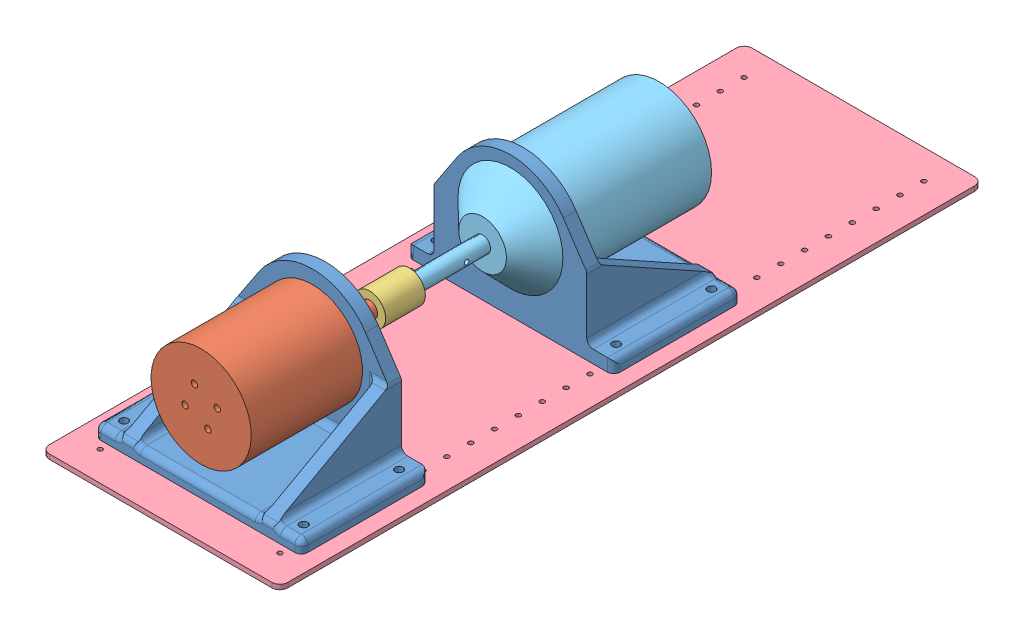
SolidWorks assembly test bed assembly, configuration Default. Lengths in mm.
Overall size (150 92.16 442).
10 component instances, 5 part files, 17 mates.
Components (placement in the parent):
- motor mount-1: motor mount [Default] at (42.5731 -25.4592 0) size (130 88 80)
- Eapmic C6374-1: Eapmic C6374 [Default] at (42.5731 -25.4592 8) x (-0.923728 -0.383049 0) z (0 0 -1) size (63 63 114)
- coupling-1: coupling [Default] at (42.5731 -25.4592 -40.5) size (20 20 25)
- fixture plate-1: fixture plate [Default] at (117.5731 -76.4592 103.5) x (0 0 -1) z (1 0 0) size (442 3 150)
- Flipsky 4125^test bed assembly-1: Flipsky 4125^test bed assembly [Default] at origin (suppressed, hidden, virtual)
- Flipsky 5062^test bed assembly-1: Flipsky 5062^test bed assembly [Default] at origin (suppressed, hidden, virtual)
- Flipsky 5085^test bed assembly-1: Flipsky 5085^test bed assembly [Default] at origin (suppressed, hidden, virtual)
- Flipsky 66112^test bed assembly-1: Flipsky 66112^test bed assembly [Default] at origin size (130 88 165) (virtual)
  - motor mount-1: motor mount [Default] at (42.5731 -25.4592 -116.5) x (-1 0 0) z (0 0 -1) size (130 88 80)
  - Flipsky 66112 Motor-1: Flipsky 66112 Motor [Default] at (42.5731 -25.4592 -163.25) size (66 66 165)
Mates (geometry in assembly coordinates):
- Coincident1: coincident: plane of motor mount-1 through (42.5731 -25.4592 0) normal (0 0 -1); plane of assembly through (0 0 0) normal (0 0 1)
- Coincident2: coincident: plane of motor mount-1 through (42.5731 -25.4592 8) normal (0 0 1); plane of Eapmic C6374-1 through (42.5731 -25.4592 8) normal (0 0 -1)
- Concentric1: concentric: circle of motor mount-1; circle of Eapmic C6374-1
- Coincident6: coincident: plane of Eapmic C6374-1 through (42.5731 -25.4592 -36) normal (0 0 -1); plane of coupling-1 through (42.5731 -25.4592 -36) normal (0 0 1)
- Concentric4: concentric: circle of Eapmic C6374-1; circle of coupling-1
- Coincident9: coincident: plane of motor mount-1 through (2.5731 -73.4592 80) normal (0 -1 0); plane of fixture plate-1 through (112.5731 -73.4592 98.5) normal (0 1 0)
- Concentric7: concentric: cylinder of motor mount-1 through (99.0731 -73.4592 70) axis (0 1 0) radius 2.5; circle of fixture plate-1
- Concentric8: concentric: circle of motor mount-1; circle of fixture plate-1
- Coincident10: coincident: plane of ? through (39.6256 65.2498 -45) normal (0 0 1); plane of coupling-1 through (39.6256 65.2498 -45) normal (0 0 -1)
- Concentric9: concentric: circle of ?; circle of coupling-1
- Coincident14: coincident: plane of coupling-1 through (39.6256 65.2498 -45) normal (0 0 -1); plane of ? through (39.6256 65.2498 -45) normal (0 0 1)
- Concentric13: concentric: circle of coupling-1; circle of ?
- Coincident18: coincident: plane of coupling-1 through (39.6256 65.2498 -45) normal (0 0 -1); plane of ? through (39.6256 65.2498 -45) normal (0 0 1)
- Concentric18: concentric: circle of coupling-1; circle of ?
- Coincident24: coincident: plane of fixture plate-1 through (112.5731 -73.4592 98.5) normal (0 1 0); plane of Flipsky 66112^test bed assembly-1/motor mount-1 through (82.5731 -73.4592 -196.5) normal (0 -1 0)
- Coincident25: coincident: plane of coupling-1 through (42.5731 -25.4592 -45) normal (0 0 -1); plane of Flipsky 66112^test bed assembly-1/Flipsky 66112 Motor-1 through (42.5731 -25.4592 -45) normal (0 0 1)
- Concentric22: concentric: circle of coupling-1; circle of Flipsky 66112^test bed assembly-1/Flipsky 66112 Motor-1
